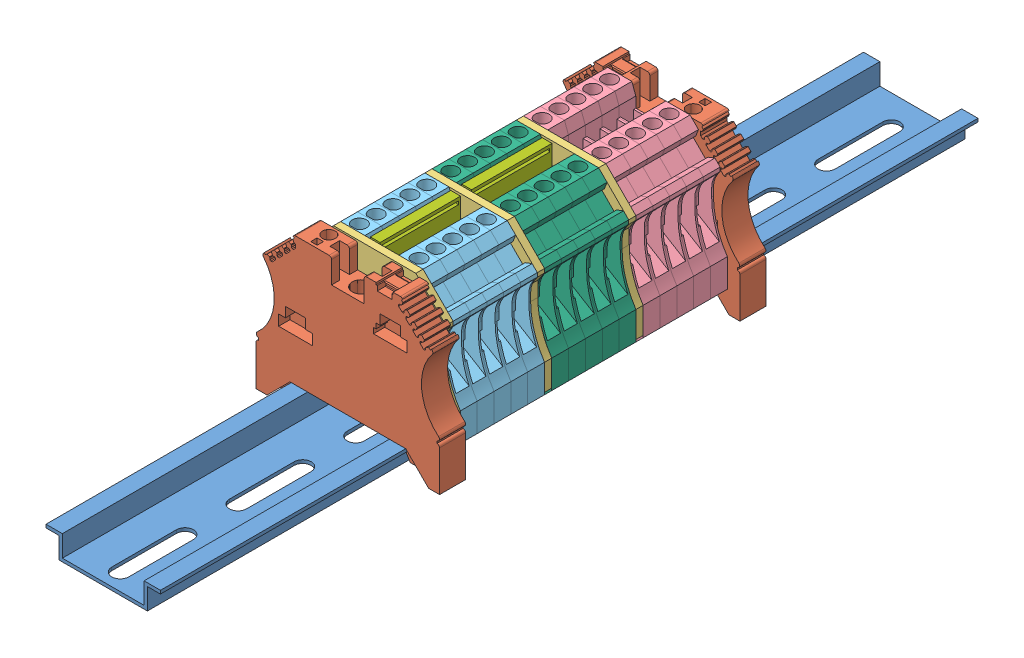
SolidWorks assembly 5xLNPE, configuration Standard. Lengths in mm.
Overall size (56.97 56.59 250).
23 component instances, 7 part files, 79 mates.
Components (placement in the parent):
- Hutschiene-1: Hutschiene [250] at (-17.5 -7.5 -250) size (35 7.5 250)
- WEW_35_2-1: WEW_35_2 [Standard] at (-45.75 -7 -174.85) x (0 0 1) z (0 1 0) size (8 56.1 46.5)
- WEW_35_2-2: WEW_35_2 [Standard] at (10.35 -7 -75) x (0 0 -1) z (0 1 0) size (8 56.1 46.5)
- D_UT_2.5_10-1: D_UT_2.5_10 [Standard] at (-46.4297 58.45 -85.2) size (47 39.8 2.2)
- D_UT_2.5_10-2: D_UT_2.5_10 [Standard] at (-46.4297 58.45 -113.15) size (47 39.8 2.2)
- D_UT_2.5_10-3: D_UT_2.5_10 [Standard] at (-46.4297 58.45 -141.1) size (47 39.8 2.2)
- UT_2.5_PE-1: UT_2.5_PE [Standard] at (-48.6989 10.6178 -141.1) x (0.992546 -0.121869 0) z (0 0 1) size (49.27 50.96 5.15)
- UT_2.5_PE-2: UT_2.5_PE [Standard] at (-48.6989 10.6178 -146.25) x (0.992546 -0.121869 0) z (0 0 1) size (49.27 50.96 5.15)
- UT_2.5_PE-3: UT_2.5_PE [Standard] at (-48.6989 10.6178 -151.4) x (0.992546 -0.121869 0) z (0 0 1) size (49.27 50.96 5.15)
- UT_2.5_PE-4: UT_2.5_PE [Standard] at (-48.6989 10.6178 -156.55) x (0.992546 -0.121869 0) z (0 0 1) size (49.27 50.96 5.15)
- UT_2.5_PE-5: UT_2.5_PE [Standard] at (-48.6989 10.6178 -161.7) x (0.992546 -0.121869 0) z (0 0 1) size (49.27 50.96 5.15)
- UT_2.5-1: UT_2.5 [Standard] at (-48.6989 10.6178 -85.2) x (0.992546 -0.121869 0) z (0 0 1) size (49.27 50.96 5.15)
- UT_2.5-2: UT_2.5 [Standard] at (-48.6989 10.6178 -90.35) x (0.992546 -0.121869 0) z (0 0 1) size (49.27 50.96 5.15)
- UT_2.5-3: UT_2.5 [Standard] at (-48.6989 10.6178 -95.5) x (0.992546 -0.121869 0) z (0 0 1) size (49.27 50.96 5.15)
- UT_2.5-4: UT_2.5 [Standard] at (-48.6989 10.6178 -100.65) x (0.992546 -0.121869 0) z (0 0 1) size (49.27 50.96 5.15)
- UT_2.5-5: UT_2.5 [Standard] at (-48.6989 10.6178 -105.8) x (0.992546 -0.121869 0) z (0 0 1) size (49.27 50.96 5.15)
- UT_2.5_BU-1: UT_2.5_BU [Standard] at (-48.6989 10.6178 -113.15) x (0.992546 -0.121869 0) z (0 0 1) size (49.27 50.96 5.15)
- UT_2.5_BU-2: UT_2.5_BU [Standard] at (-48.6989 10.6178 -118.3) x (0.992546 -0.121869 0) z (0 0 1) size (49.27 50.96 5.15)
- UT_2.5_BU-3: UT_2.5_BU [Standard] at (-48.6989 10.6178 -123.45) x (0.992546 -0.121869 0) z (0 0 1) size (49.27 50.96 5.15)
- UT_2.5_BU-4: UT_2.5_BU [Standard] at (-48.6989 10.6178 -128.6) x (0.992546 -0.121869 0) z (0 0 1) size (49.27 50.96 5.15)
- UT_2.5_BU-5: UT_2.5_BU [Standard] at (-48.6989 10.6178 -133.75) x (0.992546 -0.121869 0) z (0 0 1) size (49.27 50.96 5.15)
- FBS_5_5-1: FBS_5_5 [Standard] at (-24.1072 48.875 -144.035) size (3 22.98 24.6)
- FBS_5_5-2: FBS_5_5 [Standard] at (-24.1072 48.875 -171.985) size (3 22.98 24.6)
Mates (geometry in assembly coordinates):
- Deckungsgleich1: coincident aligned: plane of Hutschiene-1 through (-17.5 -7.5 0) normal (0 0 1); plane of assembly through (0 0 0) normal (0 0 1)
- Deckungsgleich2: coincident aligned: plane of Hutschiene-1 through (-30 0 0) normal (0 1 0); plane of assembly through (0 0 0) normal (0 1 0)
- Deckungsgleich3: coincident aligned: plane of Hutschiene-1 through (0 -1 0) normal (1 0 0); plane of assembly through (0 0 0) normal (1 0 0)
- Abstand1: distance = 75 mm aligned: plane of WEW_35_2-2 through (-17.7 0 -75) normal (0 0 1); plane of Hutschiene-1 through (-17.5 -7.5 0) normal (0 0 1)
- Deckungsgleich70: coincident anti-aligned: plane of Hutschiene-1 through (0 0 0) normal (0 1 0); plane of ? through (-54.05 0 -193.75) normal (0 -1 0)
- Deckungsgleich71: coincident anti-aligned: plane of Hutschiene-1 through (-30 0 0) normal (0 1 0); plane of ? through (-54.05 0 -238.75) normal (0 -1 0)
- Deckungsgleich72: coincident anti-aligned: plane of Hutschiene-1 through (-30 0 0) normal (0 1 0); plane of ? through (-54.05 0 -283.75) normal (0 -1 0)
- Deckungsgleich73: coincident anti-aligned: plane of Hutschiene-1 through (0 -1 0) normal (1 0 0); plane of ? through (0 8.9 -167.85) normal (-1 0 0)
- Deckungsgleich74: coincident anti-aligned: plane of Hutschiene-1 through (0 -1 0) normal (1 0 0); plane of ? through (0 8.9 -212.85) normal (-1 0 0)
- Deckungsgleich75: coincident anti-aligned: plane of Hutschiene-1 through (0 -1 0) normal (1 0 0); plane of ? through (0 8.9 -257.85) normal (-1 0 0)
- Deckungsgleich77: coincident anti-aligned: plane of ? through (-17.75 2.45 -211.85) normal (0 0 -1); plane of ? through (-17.75 2.45 -211.85) normal (0 0 1)
- Deckungsgleich78: coincident anti-aligned: plane of ? through (-17.75 2.45 -256.85) normal (0 0 -1); plane of ? through (-17.75 2.45 -256.85) normal (0 0 1)
- Deckungsgleich81: coincident anti-aligned: plane of Hutschiene-1 through (-30 0 0) normal (0 1 0); plane of WEW_35_2-2 through (-35.4 0 -83) normal (0 -1 0)
- Deckungsgleich82: coincident anti-aligned: plane of Hutschiene-1 through (-30 0 0) normal (0 1 0); plane of UT_2.5-1 through (-7.7 0 -85.2) normal (0 -1 0)
- Deckungsgleich83: coincident anti-aligned: plane of Hutschiene-1 through (-30 0 0) normal (0 1 0); plane of UT_2.5-2 through (-7.7 0 -90.35) normal (0 -1 0)
- Deckungsgleich84: coincident anti-aligned: plane of Hutschiene-1 through (-30 0 0) normal (0 1 0); plane of UT_2.5-3 through (-7.7 0 -95.5) normal (0 -1 0)
- Deckungsgleich85: coincident anti-aligned: plane of Hutschiene-1 through (-30 0 0) normal (0 1 0); plane of UT_2.5-4 through (-7.7 0 -100.65) normal (0 -1 0)
- Deckungsgleich86: coincident anti-aligned: plane of Hutschiene-1 through (-30 0 0) normal (0 1 0); plane of UT_2.5-5 through (-7.7 0 -105.8) normal (0 -1 0)
- Deckungsgleich87: coincident aligned: plane of D_UT_2.5_10-1 through (4.3 30.8 -84.1) normal (1 0 0); plane of UT_2.5-1 through (4.3 30.8 -85.2) normal (1 0 0)
- Deckungsgleich88: coincident aligned: line of D_UT_2.5_10-1 through (4.3 29.6 -85.2) axis (0 0 1); line of UT_2.5-1 through (4.3 29.6 -90.35) axis (0 0 1)
- Deckungsgleich89: coincident anti-aligned: plane of D_UT_2.5_10-1 through (8.926 -3.78 -85.2) normal (0 0 -1); plane of UT_2.5-1 through (0 0 -85.2) normal (0 0 1)
- Deckungsgleich90: coincident anti-aligned: plane of UT_2.5-1 through (0 0 -90.35) normal (0 0 -1); plane of UT_2.5-2 through (0 0 -90.35) normal (0 0 1)
- Deckungsgleich91: coincident anti-aligned: plane of UT_2.5-2 through (0 0 -95.5) normal (0 0 -1); plane of UT_2.5-3 through (0 0 -95.5) normal (0 0 1)
- Deckungsgleich92: coincident anti-aligned: plane of UT_2.5-3 through (0 0 -100.65) normal (0 0 -1); plane of UT_2.5-4 through (0 0 -100.65) normal (0 0 1)
- Deckungsgleich93: coincident anti-aligned: plane of UT_2.5-4 through (0 0 -105.8) normal (0 0 -1); plane of UT_2.5-5 through (0 0 -105.8) normal (0 0 1)
- Deckungsgleich94: coincident anti-aligned: plane of Hutschiene-1 through (0 -1 0) normal (1 0 0); plane of UT_2.5-1 through (0 -1.1 -85.2) normal (-1 0 0)
- Deckungsgleich95: coincident anti-aligned: plane of Hutschiene-1 through (0 -1 0) normal (1 0 0); plane of UT_2.5-2 through (0 -1.1 -90.35) normal (-1 0 0)
- Deckungsgleich96: coincident anti-aligned: plane of Hutschiene-1 through (0 -1 0) normal (1 0 0); plane of UT_2.5-3 through (0 -1.1 -95.5) normal (-1 0 0)
- Deckungsgleich97: coincident anti-aligned: plane of Hutschiene-1 through (0 -1 0) normal (1 0 0); plane of UT_2.5-4 through (0 -1.1 -100.65) normal (-1 0 0)
- Deckungsgleich98: coincident anti-aligned: plane of Hutschiene-1 through (0 -1 0) normal (1 0 0); plane of UT_2.5-5 through (0 -1.1 -105.8) normal (-1 0 0)
- Deckungsgleich99: coincident anti-aligned: plane of WEW_35_2-2 through (-17.7 0 -83) normal (0 0 -1); plane of D_UT_2.5_10-1 through (-31.3534 31.331 -83) normal (0 0 1)
- Deckungsgleich101: coincident: plane of Hutschiene-1 through (0 -1 0) normal (1 0 0); line of WEW_35_2-2 through (0 0 -83) axis (0 0 1)
- Deckungsgleich102: coincident anti-aligned: plane of UT_2.5-1 through (-18.35 21.85 -85.675) normal (0 0 -1); plane of FBS_5_5-1 through (-18.5 39.7 -85.675) normal (0 0 1)
- Deckungsgleich103: coincident anti-aligned: plane of UT_2.5-2 through (-21.5 36.703 -90.35) normal (1 0 0); plane of FBS_5_5-1 through (-21.5 38.7586 -99.6095) normal (-1 0 0)
- Deckungsgleich104: coincident aligned: plane of UT_2.5-1 through (-30.1 40 -85.2) normal (0 1 0); plane of FBS_5_5-1 through (-18.5 40 -96.075) normal (0 1 0)
- Deckungsgleich105: coincident anti-aligned: plane of D_UT_2.5_10-2 through (8.926 -3.78 -113.15) normal (0 0 -1); plane of UT_2.5_BU-1 through (0 0 -113.15) normal (0 0 1)
- Deckungsgleich106: coincident anti-aligned: plane of UT_2.5_BU-1 through (0 0 -118.3) normal (0 0 -1); plane of UT_2.5_BU-2 through (0 0 -118.3) normal (0 0 1)
- Deckungsgleich107: coincident anti-aligned: plane of UT_2.5_BU-2 through (0 0 -123.45) normal (0 0 -1); plane of UT_2.5_BU-3 through (0 0 -123.45) normal (0 0 1)
- Deckungsgleich108: coincident anti-aligned: plane of UT_2.5_BU-3 through (0 0 -128.6) normal (0 0 -1); plane of UT_2.5_BU-4 through (0 0 -128.6) normal (0 0 1)
- Deckungsgleich109: coincident anti-aligned: plane of UT_2.5_BU-4 through (0 0 -133.75) normal (0 0 -1); plane of UT_2.5_BU-5 through (0 0 -133.75) normal (0 0 1)
- Deckungsgleich110: coincident anti-aligned: plane of Hutschiene-1 through (-30 0 0) normal (0 1 0); plane of UT_2.5_BU-1 through (-7.7 0 -113.15) normal (0 -1 0)
- Deckungsgleich111: coincident anti-aligned: plane of Hutschiene-1 through (-30 0 0) normal (0 1 0); plane of UT_2.5_BU-2 through (-7.7 0 -118.3) normal (0 -1 0)
- Deckungsgleich112: coincident anti-aligned: plane of Hutschiene-1 through (-30 0 0) normal (0 1 0); plane of UT_2.5_BU-3 through (-7.7 0 -123.45) normal (0 -1 0)
- Deckungsgleich113: coincident anti-aligned: plane of Hutschiene-1 through (-30 0 0) normal (0 1 0); plane of UT_2.5_BU-4 through (-7.7 0 -128.6) normal (0 -1 0)
- Deckungsgleich114: coincident anti-aligned: plane of Hutschiene-1 through (-30 0 0) normal (0 1 0); plane of UT_2.5_BU-5 through (-7.7 0 -133.75) normal (0 -1 0)
- Deckungsgleich115: coincident aligned: plane of D_UT_2.5_10-2 through (4.3 30.8 -112.05) normal (1 0 0); plane of UT_2.5_BU-1 through (4.3 30.8 -113.15) normal (1 0 0)
- Deckungsgleich116: coincident aligned: line of D_UT_2.5_10-2 through (4.3 29.6 -113.15) axis (0 0 1); line of UT_2.5_BU-1 through (4.3 29.6 -118.3) axis (0 0 1)
- Deckungsgleich117: coincident anti-aligned: plane of Hutschiene-1 through (0 -1 0) normal (1 0 0); plane of UT_2.5_BU-1 through (0 -1.1 -113.15) normal (-1 0 0)
- Deckungsgleich118: coincident anti-aligned: plane of Hutschiene-1 through (0 -1 0) normal (1 0 0); plane of UT_2.5_BU-2 through (0 -1.1 -118.3) normal (-1 0 0)
- Deckungsgleich119: coincident anti-aligned: plane of Hutschiene-1 through (0 -1 0) normal (1 0 0); plane of UT_2.5_BU-3 through (0 -1.1 -123.45) normal (-1 0 0)
- Deckungsgleich120: coincident anti-aligned: plane of Hutschiene-1 through (0 -1 0) normal (1 0 0); plane of UT_2.5_BU-4 through (0 -1.1 -128.6) normal (-1 0 0)
- Deckungsgleich121: coincident anti-aligned: plane of Hutschiene-1 through (0 -1 0) normal (1 0 0); plane of UT_2.5_BU-5 through (0 -1.1 -133.75) normal (-1 0 0)
- Deckungsgleich122: coincident anti-aligned: plane of D_UT_2.5_10-2 through (-31.3534 31.331 -110.95) normal (0 0 1); plane of UT_2.5-5 through (0 0 -110.95) normal (0 0 -1)
- Deckungsgleich123: coincident anti-aligned: plane of UT_2.5_BU-1 through (-18.35 21.85 -113.625) normal (0 0 -1); plane of FBS_5_5-2 through (-18.5 39.7 -113.625) normal (0 0 1)
- Deckungsgleich124: coincident anti-aligned: plane of UT_2.5_BU-1 through (-21.5 36.703 -113.15) normal (1 0 0); plane of FBS_5_5-2 through (-21.5 38.7586 -127.5595) normal (-1 0 0)
- Deckungsgleich125: coincident aligned: plane of UT_2.5_BU-1 through (-30.1 40 -113.15) normal (0 1 0); plane of FBS_5_5-2 through (-18.5 40 -124.025) normal (0 1 0)
- Deckungsgleich126: coincident anti-aligned: plane of D_UT_2.5_10-3 through (8.926 -3.78 -141.1) normal (0 0 -1); plane of UT_2.5_PE-1 through (0 0 -141.1) normal (0 0 1)
- Deckungsgleich127: coincident anti-aligned: plane of UT_2.5_PE-1 through (0 0 -146.25) normal (0 0 -1); plane of UT_2.5_PE-2 through (0 0 -146.25) normal (0 0 1)
- Deckungsgleich128: coincident anti-aligned: plane of UT_2.5_PE-2 through (0 0 -151.4) normal (0 0 -1); plane of UT_2.5_PE-3 through (0 0 -151.4) normal (0 0 1)
- Deckungsgleich129: coincident anti-aligned: plane of UT_2.5_PE-3 through (0 0 -156.55) normal (0 0 -1); plane of UT_2.5_PE-4 through (0 0 -156.55) normal (0 0 1)
- Deckungsgleich130: coincident anti-aligned: plane of UT_2.5_PE-4 through (0 0 -161.7) normal (0 0 -1); plane of UT_2.5_PE-5 through (0 0 -161.7) normal (0 0 1)
- Deckungsgleich131: coincident aligned: plane of D_UT_2.5_10-3 through (4.3 30.8 -140) normal (1 0 0); plane of UT_2.5_PE-1 through (4.3 30.8 -141.1) normal (1 0 0)
- Deckungsgleich132: coincident aligned: line of D_UT_2.5_10-3 through (4.3 30.8 -141.1) axis (0 0 1); line of UT_2.5_PE-1 through (4.3 30.8 -146.25) axis (0 0 1)
- Deckungsgleich133: coincident anti-aligned: plane of Hutschiene-1 through (-30 0 0) normal (0 1 0); plane of UT_2.5_PE-5 through (-7.7 0 -161.7) normal (0 -1 0)
- Deckungsgleich134: coincident anti-aligned: plane of Hutschiene-1 through (-30 0 0) normal (0 1 0); plane of UT_2.5_PE-4 through (-7.7 0 -156.55) normal (0 -1 0)
- Deckungsgleich135: coincident anti-aligned: plane of Hutschiene-1 through (-30 0 0) normal (0 1 0); plane of UT_2.5_PE-3 through (-7.7 0 -151.4) normal (0 -1 0)
- Deckungsgleich136: coincident anti-aligned: plane of Hutschiene-1 through (-30 0 0) normal (0 1 0); plane of UT_2.5_PE-2 through (-7.7 0 -146.25) normal (0 -1 0)
- Deckungsgleich137: coincident anti-aligned: plane of Hutschiene-1 through (-30 0 0) normal (0 1 0); plane of UT_2.5_PE-1 through (-7.7 0 -141.1) normal (0 -1 0)
- Deckungsgleich138: coincident anti-aligned: plane of Hutschiene-1 through (0 -1 0) normal (1 0 0); plane of UT_2.5_PE-1 through (0 -1.1 -141.1) normal (-1 0 0)
- Deckungsgleich139: coincident anti-aligned: plane of Hutschiene-1 through (0 -1 0) normal (1 0 0); plane of UT_2.5_PE-2 through (0 -1.1 -146.25) normal (-1 0 0)
- Deckungsgleich140: coincident anti-aligned: plane of Hutschiene-1 through (0 -1 0) normal (1 0 0); plane of UT_2.5_PE-3 through (0 -1.1 -151.4) normal (-1 0 0)
- Deckungsgleich141: coincident anti-aligned: plane of Hutschiene-1 through (0 -1 0) normal (1 0 0); plane of UT_2.5_PE-4 through (0 -1.1 -156.55) normal (-1 0 0)
- Deckungsgleich142: coincident anti-aligned: plane of Hutschiene-1 through (0 -1 0) normal (1 0 0); plane of UT_2.5_PE-5 through (0 -1.1 -161.7) normal (-1 0 0)
- Deckungsgleich143: coincident anti-aligned: plane of D_UT_2.5_10-3 through (-31.3534 31.331 -138.9) normal (0 0 1); plane of UT_2.5_BU-5 through (0 0 -138.9) normal (0 0 -1)
- Deckungsgleich144: coincident anti-aligned: plane of UT_2.5_PE-5 through (0 0 -166.85) normal (0 0 -1); plane of ? through (-17.75 2.45 -166.85) normal (0 0 1)
- Deckungsgleich145: coincident anti-aligned: plane of WEW_35_2-1 through (-17.7 0 -301.85) normal (0 0 1); plane of ? through (-17.75 2.45 -301.85) normal (0 0 -1)
- Deckungsgleich146: coincident anti-aligned: plane of Hutschiene-1 through (0 0 0) normal (0 1 0); plane of WEW_35_2-1 through (0 0 -166.85) normal (0 -1 0)
- Deckungsgleich147: coincident anti-aligned: line of Hutschiene-1 through (0 0 0) axis (0 0 -1); line of WEW_35_2-1 through (0 0 -174.85) axis (0 0 1)
- Deckungsgleich148: coincident anti-aligned: plane of WEW_35_2-1 through (-17.7 0 -166.85) normal (0 0 1); plane of UT_2.5_PE-5 through (0 0 -166.85) normal (0 0 -1)
